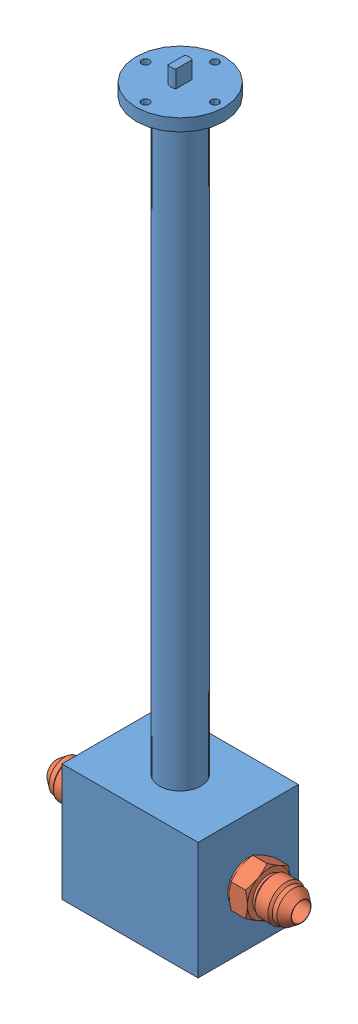
SolidWorks assembly cryo_subassy_test, configuration Default. Lengths in mm.
Overall size (146.75 381 52.07).
3 component instances, 2 part files, 5 mates.
Components (placement in the parent):
- FAKE_Cryo_SOV_nohandle-1: FAKE_Cryo_SOV_nohandle [Default] at origin size (70.61 381 52.07)
- 0500_OD_JIC_to_0500_NPT-1: 0500_OD_JIC_to_0500_NPT [50715K802] at (40.132 -335.28 0) size (55.21 25.66 22.23)
- 0500_OD_JIC_to_0500_NPT-3: 0500_OD_JIC_to_0500_NPT [50715K802] at (-41.402 -335.28 0) x (-1 0 0) z (0 0 1) size (55.21 25.66 22.23)
Mates (geometry in assembly coordinates):
- Concentric2: concentric aligned: cylinder of FAKE_Cryo_SOV_nohandle-1 through (-35.306 -335.28 0) axis (1 0 0) radius 7.112; cylinder of 0500_OD_JIC_to_0500_NPT-1 through (62.738 -335.28 0) axis (1 0 0) radius 4.953
- Distance5: distance = 1.27 mm anti-aligned: plane of 0500_OD_JIC_to_0500_NPT-1 through (36.576 -316.0326 11.1125) normal (-1 0 0); plane of FAKE_Cryo_SOV_nohandle-1 through (35.306 -365.76 26.035) normal (1 0 0)
- Concentric3: concentric anti-aligned: cylinder of FAKE_Cryo_SOV_nohandle-1 through (-35.306 -335.28 0) axis (1 0 0) radius 7.112; cylinder of 0500_OD_JIC_to_0500_NPT-3 through (-64.008 -335.28 0) axis (-1 0 0) radius 4.953
- Distance6: distance = 2.54 mm anti-aligned: plane of 0500_OD_JIC_to_0500_NPT-3 through (-37.846 -354.5274 11.1125) normal (1 0 0); plane of FAKE_Cryo_SOV_nohandle-1 through (-35.306 -365.76 26.035) normal (-1 0 0)
- Coincident1: coincident aligned: plane of 0500_OD_JIC_to_0500_NPT-3 through (-41.402 -335.28 0) normal (0 0 1)
